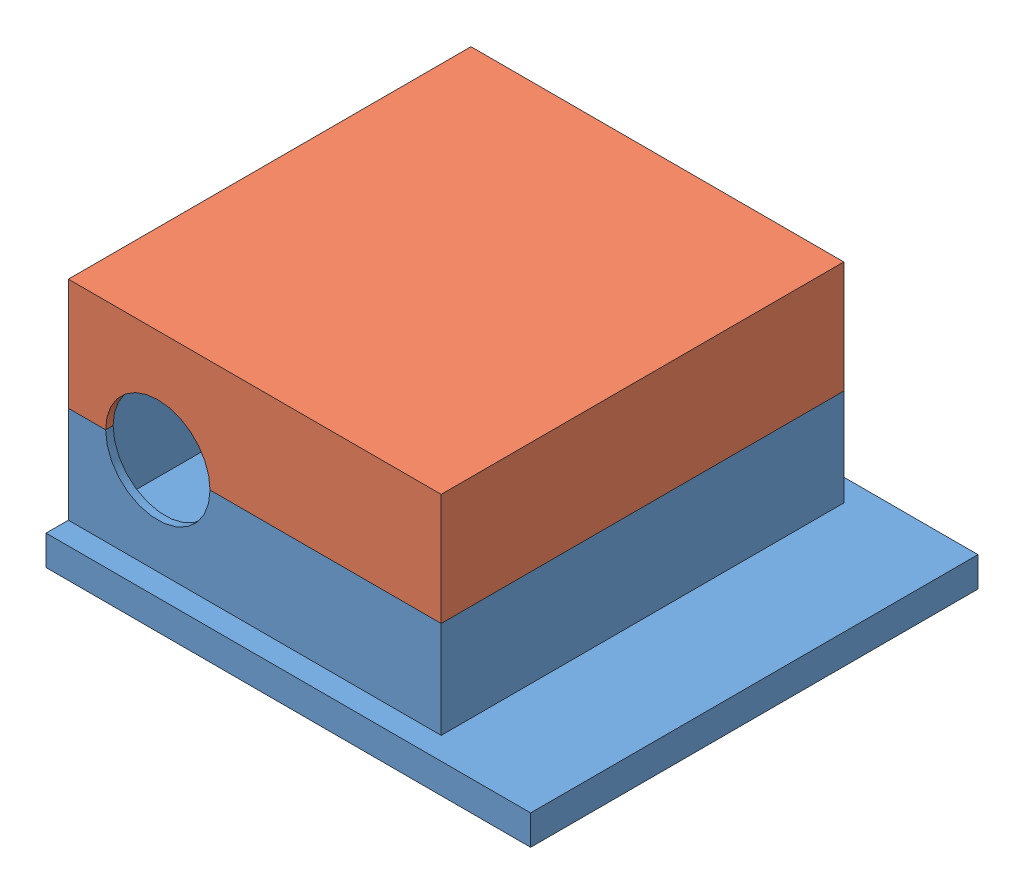
SolidWorks assembly Assemblage pied BMO 2 PART, configuration Défaut. Lengths in mm.
Overall size (32.5 16 30).
2 component instances, 2 part files, 3 mates.
Components (placement in the parent):
- pied BMO part 1-1: pied BMO part 1 [Défaut] at (2.1332 -6.4778 32.5) size (32.5 8.5 30)
- pied BMO part 2-1: pied BMO part 2 [Défaut] at (-7.4087 8.5222 31.5361) x (0 0 1) z (1 0 0) size (27 7.5 25)
Mates (geometry in assembly coordinates):
- Coïncidente7: coincident: line of pied BMO part 1-1 through (6.7122 2.0222 8.7105) axis (-1 0 0); line of pied BMO part 2-1 through (6.7122 2.0222 8.7105) axis (-1 0 0)
- Coïncidente9: coincident: line of pied BMO part 1-1 through (-8.7878 2.0222 35.7105) axis (1 0 0); line of pied BMO part 2-1 through (-8.7878 2.0222 35.7105) axis (1 0 0)
- Coïncidente10: coincident aligned: line of pied BMO part 1-1 through (6.7122 2.0222 35.7105) axis (0 0 -1); line of pied BMO part 2-1 through (6.7122 2.0222 35.7105) axis (0 0 -1)
